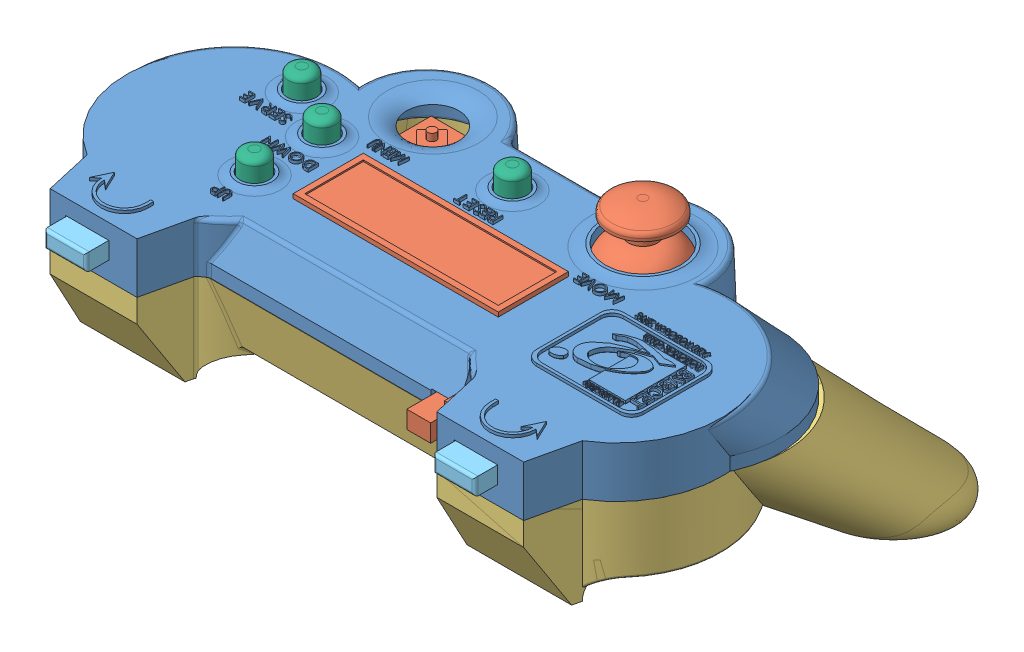
SolidWorks assembly Remote, configuration Default. Lengths in mm.
Overall size (236.65 91.98 147.18).
11 component instances, 6 part files, 23 mates.
Components (placement in the parent):
- Cover-1: Cover [Default] at (114.2138 37.0699 197.9201) size (214.82 48.01 113.46)
- Remote CKT-1: Remote CKT [Default] at (249.1354 105.0622 147.3604) x (-1 0 0) z (0 0 -1) size (156.38 57.59 102.64)
- base-2: base [Default] at (114.2138 105.3055 197.9201) size (236.65 58.6 139.42)
- base-3: base [Default] at (114.2138 105.3055 197.9201) size (236.65 58.6 139.42)
- BATTERY-1: BATTERY [Default] at (19.2212 71.889 144.1662) x (0.8775 -0.060857 -0.4757) z (0.266671 -0.762509 0.589463) size (26 48 17)
- sqr_button-1: sqr_button [Default] at (45.4692 118.7699 252.8355) size (19.6 5.9 14.59)
- button-10: button [Default] at (47.1191 134.9449 181.4155) x (0.857929 0 0.513768) z (0 -1 0) size (13 13 14.1)
- button-11: button [Default] at (63.6891 134.9449 214.3155) x (0.812318 0 0.583215) z (0 -1 0) size (13 13 14.1)
- button-12: button [Default] at (112.7791 134.9449 174.3755) x (0.987363 0 -0.158472) z (0 -1 0) size (13 13 14.1)
- button-13: button [Default] at (63.8591 134.9449 191.1655) x (0.988415 0 -0.151778) z (0 -1 0) size (13 13 14.1)
- sqr_button-2: sqr_button [Default] at (179.7138 118.7699 252.8355) size (19.6 5.9 14.59)
Mates (geometry in assembly coordinates):
- Coincident8: coincident anti-aligned: line of Cover-1 through (34.5591 113.6754 251.0355) axis (0 1 0); line of Remote CKT-1 through (34.5591 114.8449 251.0355) axis (0 -1 0)
- Parallel5: parallel anti-aligned: plane of Cover-1 through (165.9638 82.0699 251.0355) normal (0 0 -1); plane of Remote CKT-1 through (166.0691 114.8449 249.9655) normal (0 0 1)
- Distance2: distance = 1 mm anti-aligned: plane of Remote CKT-1 through (101.9991 123.4449 195.1655) normal (0 1 0); plane of Cover-1 through (69.2138 124.4449 160.4201) normal (0 -1 0)
- Concentric2: concentric anti-aligned: cone of Cover-1 through (151.7138 113.6754 167.9201) axis (0 1 0); cone of base-2 through (151.7138 86.5555 167.9201) axis (0 -1 0)
- Coincident17: coincident anti-aligned: plane of Cover-1 through (24.6818 109.5504 161.214) normal (0 -1 0); plane of base-2 through (227.8612 109.5504 55.4201) normal (0 1 0)
- Coincident18: coincident aligned: plane of Cover-1 through (62.4638 82.0699 253.6605) normal (0 0 1); plane of base-2 through (62.4638 79.0555 253.6605) normal (0 0 1)
- Coincident19: coincident anti-aligned: plane of Cover-1 through (24.6818 109.5504 161.214) normal (0 -1 0); plane of base-3 through (227.8612 109.5504 55.4201) normal (0 1 0)
- Coincident21: coincident aligned: plane of Cover-1 through (32.4638 82.0699 253.6605) normal (-0.975133 0 0.221621); plane of base-3 through (32.4638 79.0555 253.6605) normal (-0.975133 0 0.221621)
- Coincident22: coincident aligned: plane of Cover-1 through (62.4638 82.0699 253.6605) normal (0 0 1); plane of base-3 through (62.4638 79.0555 253.6605) normal (0 0 1)
- Coincident25: coincident anti-aligned: plane of Cover-1 through (52.7192 121.7199 242.6605) normal (-1 0 0); plane of sqr_button-1 through (52.7192 121.7199 255.4255) normal (1 0 0)
- Coincident26: coincident anti-aligned: plane of Cover-1 through (37.7192 121.7199 242.6605) normal (0 -1 0); plane of sqr_button-1 through (38.2192 121.7199 255.4255) normal (0 1 0)
- Coincident27: coincident anti-aligned: plane of Remote CKT-1 through (45.7091 118.6199 252.8355) normal (0 0 1); plane of sqr_button-1 through (45.4692 118.7699 252.8355) normal (0 0 -1)
- Concentric14: concentric anti-aligned: cylinder of Cover-1 through (47.1191 134.4449 181.4155) axis (0 -1 0) radius 5; cylinder of button-10 through (47.1191 124.9449 181.4155) axis (0 1 0) radius 4.65
- Coincident46: coincident anti-aligned: plane of Remote CKT-1 through (47.1191 120.9449 181.4155) normal (0 1 0); plane of button-10 through (47.1191 120.9449 181.4155) normal (0 -1 0)
- Concentric15: concentric anti-aligned: cylinder of Cover-1 through (63.8591 134.4449 191.1655) axis (0 -1 0) radius 5; cylinder of button-13 through (63.8591 124.9449 191.1655) axis (0 1 0) radius 4.65
- Concentric18: concentric anti-aligned: cylinder of Cover-1 through (63.6891 134.4449 214.3155) axis (0 -1 0) radius 5; cylinder of button-11 through (63.6891 124.9449 214.3155) axis (0 1 0) radius 4.65
- Concentric19: concentric anti-aligned: cylinder of Cover-1 through (112.7791 134.4449 174.3755) axis (0 -1 0) radius 5; cylinder of button-12 through (112.7791 124.9449 174.3755) axis (0 1 0) radius 4.65
- Coincident47: coincident anti-aligned: plane of Remote CKT-1 through (63.6891 120.9449 214.3155) normal (0 1 0); plane of button-12 through (112.7791 120.9449 174.3755) normal (0 -1 0)
- Coincident48: coincident anti-aligned: plane of Remote CKT-1 through (63.8591 120.9449 191.1655) normal (0 1 0); plane of button-13 through (63.8591 120.9449 191.1655) normal (0 -1 0)
- Coincident49: coincident anti-aligned: plane of Remote CKT-1 through (63.6891 120.9449 214.3155) normal (0 1 0); plane of button-11 through (63.6891 120.9449 214.3155) normal (0 -1 0)
- Coincident50: coincident anti-aligned: plane of Cover-1 through (186.9638 121.7199 242.6605) normal (-1 0 0); plane of sqr_button-2 through (186.9638 121.7199 255.4255) normal (1 0 0)
- Coincident51: coincident anti-aligned: plane of Cover-1 through (171.9638 121.7199 242.6605) normal (0 -1 0); plane of sqr_button-2 through (172.4638 121.7199 255.4255) normal (0 1 0)
- Coincident52: coincident aligned: plane of sqr_button-1 through (45.4692 118.7699 261.4255) normal (0 0 1); plane of sqr_button-2 through (179.7138 118.7699 261.4255) normal (0 0 1)
